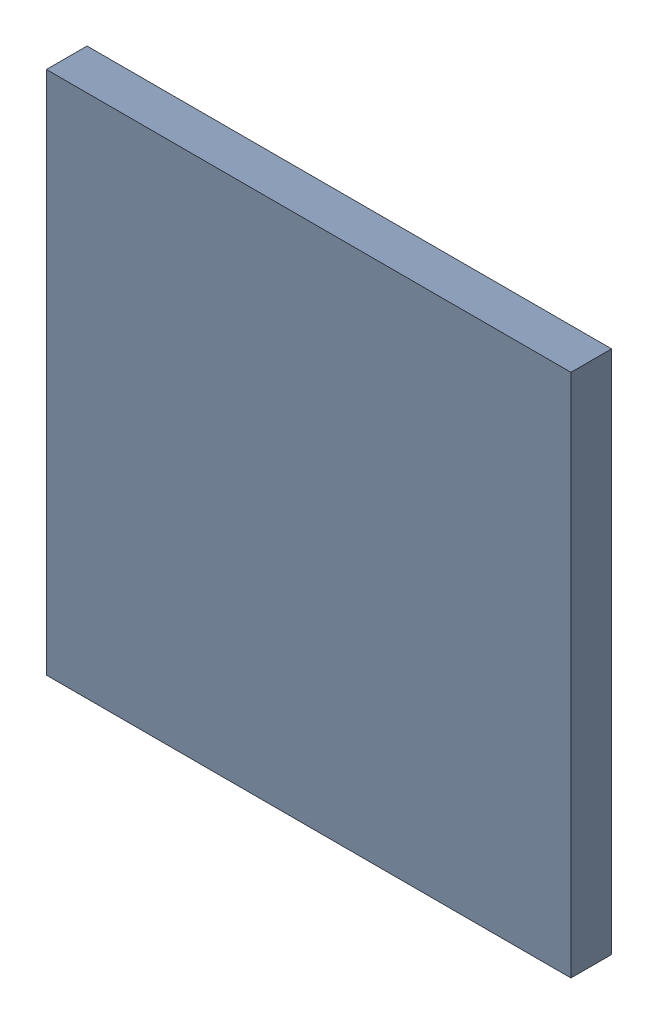
SolidWorks assembly XMC4500, configuration Standard. Lengths in mm.
Overall size (20 20 1.55).
2 component instances, 1 part files, 0 mates.
Components (placement in the parent):
- 668289720-1: 668289720 [Standard] at (-4.55 0 0.05) size (20 20 1.55)
  - Extruded_34-1: Extruded_34 [Standard] at origin size (20 20 1.55)
